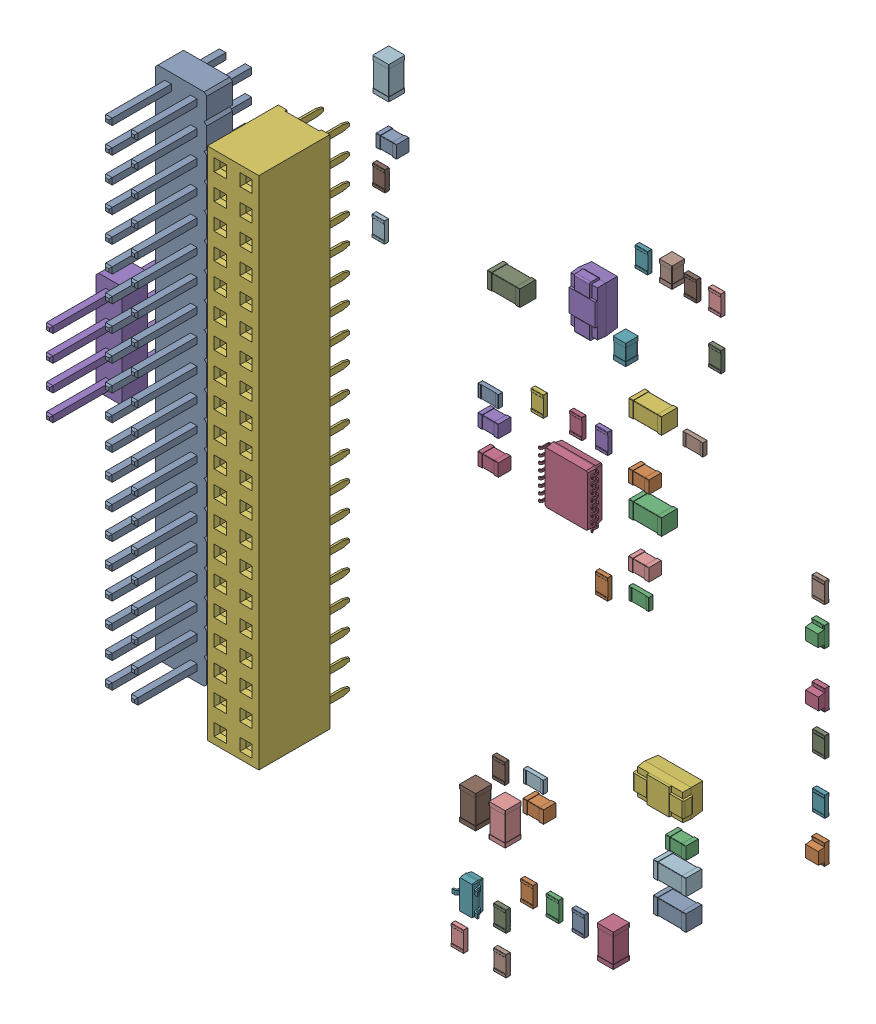
SolidWorks assembly Step_Models, configuration 默认. Lengths in mm.
Overall size (69.83 72.3 12.36).
54 component instances, 52 part files, 0 mates.
Components (placement in the parent):
- Top-1: Top [默认] at origin size (69.83 50.8 11.64)
  - J6_PinHeader_2x20_P254mm_Vertical_5E973953-1: J6_PinHeader_2x20_P254mm_Vertical_5E973953 [默认] at (34.12 74.135 0) size (5.08 50.8 11.54)
  - D1_LED_0805_2012Metric_5E97381B-1: D1_LED_0805_2012Metric_5E97381B [默认] at (96.209 38.751 0) x (0 1 0) z (0 0 1) size (2 1.25 1.1)
  - D3_LED_0805_2012Metric_5E973846-1: D3_LED_0805_2012Metric_5E973846 [默认] at (96.182 57.3275 0) x (0 1 0) z (0 0 1) size (2 1.25 1.1)
  - D5_LED_0805_2012Metric_5E973871-1: D5_LED_0805_2012Metric_5E973871 [默认] at (96.218 51.946 0) x (0 -1 0) z (0 0 1) size (2 1.25 1.1)
  - J2_PinHeader_1x04_P254mm_Vertical_5E9738C1-1: J2_PinHeader_1x04_P254mm_Vertical_5E9738C1 [默认] at (28.278 53.434 0) size (2.54 10.16 11.54)
  - J5_PinSocket_2x20_P254mm_Vertical_5E975A58-1: J5_PinSocket_2x20_P254mm_Vertical_5E975A58 [默认] at (46.26 74.13 0) size (5.08 50.8 10.1)
  - R4_R_0805_2012Metric_5E99E94D-1: R4_R_0805_2012Metric_5E99E94D [默认] at (96.209 42.815 0) x (0 -1 0) z (0 0 1) size (2 1.2 0.45)
  - R18_R_0805_2012Metric_5E9C048F-1: R18_R_0805_2012Metric_5E9C048F [默认] at (96.182 61.059 0) x (0 -1 0) z (0 0 1) size (2 1.2 0.45)
  - R21_R_0805_2012Metric_5E973B6B-1: R21_R_0805_2012Metric_5E973B6B [默认] at (96.218 47.882 0) x (0 -1 0) z (0 0 1) size (2 1.2 0.45)
- Bot-1: Bot [默认] at origin size (34.4 72.3 2.22)
  - C5_C_0805_2012Metric_5E97372B-1: C5_C_0805_2012Metric_5E97372B [默认] at (76.411 51.91 -1.6) x (1 0 0) z (0 0 -1) size (2 1.25 1.25)
  - R15_R_0805_2012Metric_5E973B05-1: R15_R_0805_2012Metric_5E973B05 [默认] at (81.491 78.453 -1.6) x (0 1 0) z (0 0 -1) size (2 1.2 0.45)
  - C1_C_1206_3216Metric_5E9736E7-1: C1_C_1206_3216Metric_5E9736E7 [默认] at (50.95 81.1 -1.6) x (0 1 0) z (0 0 -1) size (3.2 1.6 1.6)
  - C2_C_0805_2012Metric_5E9736F8-1: C2_C_0805_2012Metric_5E9736F8 [默认] at (51.5 75.6 -1.6) x (-1 0 0) z (0 0 -1) size (2 1.25 1.25)
  - C3_C_0805_2012Metric_5E973709-1: C3_C_0805_2012Metric_5E973709 [默认] at (76.411 59.403 -1.6) x (-1 0 0) z (0 0 -1) size (2 1.25 1.25)
  - C4_C_1206_3216Metric_5E97BBAC-1: C4_C_1206_3216Metric_5E97BBAC [默认] at (77.046 56.609 -1.6) x (-1 0 0) z (0 0 -1) size (3.2 1.6 1.6)
  - C6_C_0805_2012Metric_5E97B6B1-1: C6_C_0805_2012Metric_5E97B6B1 [默认] at (61.552 53.434 -1.6) x (-1 0 0) z (0 0 -1) size (2 1.25 1.25)
  - C7_C_0805_2012Metric_5E97374D-1: C7_C_0805_2012Metric_5E97374D [默认] at (61.552 56.736 -1.6) x (1 0 0) z (0 0 -1) size (2 1.25 1.25)
  - C8_C_1206_3216Metric_5E97375E-1: C8_C_1206_3216Metric_5E97375E [默认] at (77.046 65.245 -1.6) x (1 0 0) z (0 0 -1) size (3.2 1.6 1.6)
  - C9_C_0805_2012Metric_5E97376F-1: C9_C_0805_2012Metric_5E97376F [默认] at (74.506 69.563 -1.6) x (0 -1 0) z (0 0 -1) size (2 1.25 1.25)
  - C10_C_0805_2012Metric_5E973780-1: C10_C_0805_2012Metric_5E973780 [默认] at (79.078 78.453 -1.6) x (0 1 0) z (0 0 -1) size (2 1.25 1.25)
  - C11_C_1206_3216Metric_5E973791-1: C11_C_1206_3216Metric_5E973791 [默认] at (63.076 69.182 -1.6) x (1 0 0) z (0 0 -1) size (3.2 1.6 1.6)
  - C12_C_1206_3216Metric_5E977737-1: C12_C_1206_3216Metric_5E977737 [默认] at (62.441 23.081 -1.6) x (0 1 0) z (0 0 -1) size (3.2 1.6 1.6)
  - C13_C_1206_3216Metric_5E978263-1: C13_C_1206_3216Metric_5E978263 [默认] at (59.52 23.081 -1.6) x (0 1 0) z (0 0 -1) size (3.2 1.6 1.6)
  - C14_C_1206_3216Metric_5E9737C4-1: C14_C_1206_3216Metric_5E9737C4 [默认] at (79.459 27.018 -1.6) x (-1 0 0) z (0 0 -1) size (3.2 1.6 1.6)
  - C15_C_1206_3216Metric_5E9737D5-1: C15_C_1206_3216Metric_5E9737D5 [默认] at (79.459 23.97 -1.6) x (-1 0 0) z (0 0 -1) size (3.2 1.6 1.6)
  - C16_C_0805_2012Metric_5E9737E6-1: C16_C_0805_2012Metric_5E9737E6 [默认] at (65.997 26.002 -1.6) x (-1 0 0) z (0 0 -1) size (2 1.25 1.25)
  - C17_C_0805_2012Metric_5E9737F7-1: C17_C_0805_2012Metric_5E9737F7 [默认] at (80.059 29.939 -1.6) x (-1 0 0) z (0 0 -1) size (2 1.25 1.25)
  - C18_C_1206_3216Metric_5E973808-1: C18_C_1206_3216Metric_5E973808 [默认] at (73.109 18.036 -1.6) x (0 -1 0) z (0 0 -1) size (3.2 1.6 1.6)
  - D2_D_SMA_5E9BCED4-1: D2_D_SMA_5E9BCED4 [默认] at (70.823 71.468 -1.6) x (0 -1 0) z (0 0 -1) size (5 2.7 2.22)
  - D4_D_SMA_5E9777E8-1: D4_D_SMA_5E9777E8 [默认] at (78.316 33.495 -1.6) x (-1 0 0) z (0 0 -1) size (5 2.7 2.22)
  - Q1_SOT_23_5E99EF72-1: Q1_SOT_23_5E99EF72 [默认] at (59.266 15.207 -1.6) x (-1 0 0) z (0 0 -1) size (2.5 3 1.2)
  - R1_R_0805_2012Metric_5E973A17-1: R1_R_0805_2012Metric_5E973A17 [默认] at (62.695 11.397 -1.6) x (0 1 0) z (0 0 -1) size (2 1.2 0.45)
  - R2_R_0805_2012Metric_5E973A28-1: R2_R_0805_2012Metric_5E973A28 [默认] at (62.695 15.207 -1.6) x (0 1 0) z (0 0 -1) size (2 1.2 0.45)
  - R3_R_0805_2012Metric_5E973A39-1: R3_R_0805_2012Metric_5E973A39 [默认] at (58.504 11.397 -1.6) x (0 -1 0) z (0 0 -1) size (2 1.2 0.45)
  - R5_R_0805_2012Metric_5E973A5B-1: R5_R_0805_2012Metric_5E973A5B [默认] at (50.75 72.5 -1.6) x (0 1 0) z (0 0 -1) size (2 1.2 0.45)
  - R6_R_0805_2012Metric_5E973A6C-1: R6_R_0805_2012Metric_5E973A6C [默认] at (50.7 68.1 -1.6) x (0 1 0) z (0 0 -1) size (2 1.2 0.45)
  - R7_R_0805_2012Metric_5E973A7D-1: R7_R_0805_2012Metric_5E973A7D [默认] at (61.552 59.276 -1.6) x (1 0 0) z (0 0 -1) size (2 1.2 0.45)
  - R8_R_0805_2012Metric_5E973A8E-1: R8_R_0805_2012Metric_5E973A8E [默认] at (72.728 48.608 -1.6) x (0 1 0) z (0 0 -1) size (2 1.2 0.45)
  - R9_R_0805_2012Metric_5E97BAD9-1: R9_R_0805_2012Metric_5E97BAD9 [默认] at (76.411 49.37 -1.6) x (-1 0 0) z (0 0 -1) size (2 1.2 0.45)
  - R10_R_0805_2012Metric_5E973AB0-1: R10_R_0805_2012Metric_5E973AB0 [默认] at (70.188 61.054 -1.6) x (0 -1 0) z (0 0 -1) size (2 1.2 0.45)
  - R11_R_0805_2012Metric_5E973AC1-1: R11_R_0805_2012Metric_5E973AC1 [默认] at (72.728 61.054 -1.6) x (0 1 0) z (0 0 -1) size (2 1.2 0.45)
  - R12_R_0805_2012Metric_5E97B756-1: R12_R_0805_2012Metric_5E97B756 [默认] at (66.378 61.054 -1.6) x (0 1 0) z (0 0 -1) size (2 1.2 0.45)
  - R13_R_0805_2012Metric_5E973AE3-1: R13_R_0805_2012Metric_5E973AE3 [默认] at (76.665 78.453 -1.6) x (0 1 0) z (0 0 -1) size (2 1.2 0.45)
  - R14_R_0805_2012Metric_5E973AF4-1: R14_R_0805_2012Metric_5E973AF4 [默认] at (81.745 65.245 -1.6) x (1 0 0) z (0 0 -1) size (2 1.2 0.45)
  - R16_R_0805_2012Metric_5E973B16-1: R16_R_0805_2012Metric_5E973B16 [默认] at (83.904 73.627 -1.6) x (0 1 0) z (0 0 -1) size (2 1.2 0.45)
  - R17_R_0805_2012Metric_5E973B27-1: R17_R_0805_2012Metric_5E973B27 [默认] at (83.904 78.453 -1.6) x (0 -1 0) z (0 0 -1) size (2 1.2 0.45)
  - R19_R_0805_2012Metric_5E973B49-1: R19_R_0805_2012Metric_5E973B49 [默认] at (62.568 27.78 -1.6) x (0 -1 0) z (0 0 -1) size (2 1.2 0.45)
  - R20_R_0805_2012Metric_5E973B5A-1: R20_R_0805_2012Metric_5E973B5A [默认] at (65.997 28.542 -1.6) x (1 0 0) z (0 0 -1) size (2 1.2 0.45)
  - R22_R_0805_2012Metric_5E973B7C-1: R22_R_0805_2012Metric_5E973B7C [默认] at (70.4133 18.636 -1.6) x (0 -1 0) z (0 0 -1) size (2 1.2 0.45)
  - R23_R_0805_2012Metric_5E9785CC-1: R23_R_0805_2012Metric_5E9785CC [默认] at (65.362 18.636 -1.6) x (0 -1 0) z (0 0 -1) size (2 1.2 0.45)
  - R24_R_0805_2012Metric_5E973B9E-1: R24_R_0805_2012Metric_5E973B9E [默认] at (67.8877 18.636 -1.6) x (0 -1 0) z (0 0 -1) size (2 1.2 0.45)
  - U1_TSSOP_16_1EP_44x5mm_Pitch065mm_EP34x5mm_5E973BE1-1: U1_TSSOP_16_1EP_44x5mm_Pitch065mm_EP34x5mm_5E973BE1 [默认] at (69.172 55.085 -1.6) x (1 0 0) z (0 0 -1) size (5.3 5.3 1.6)
